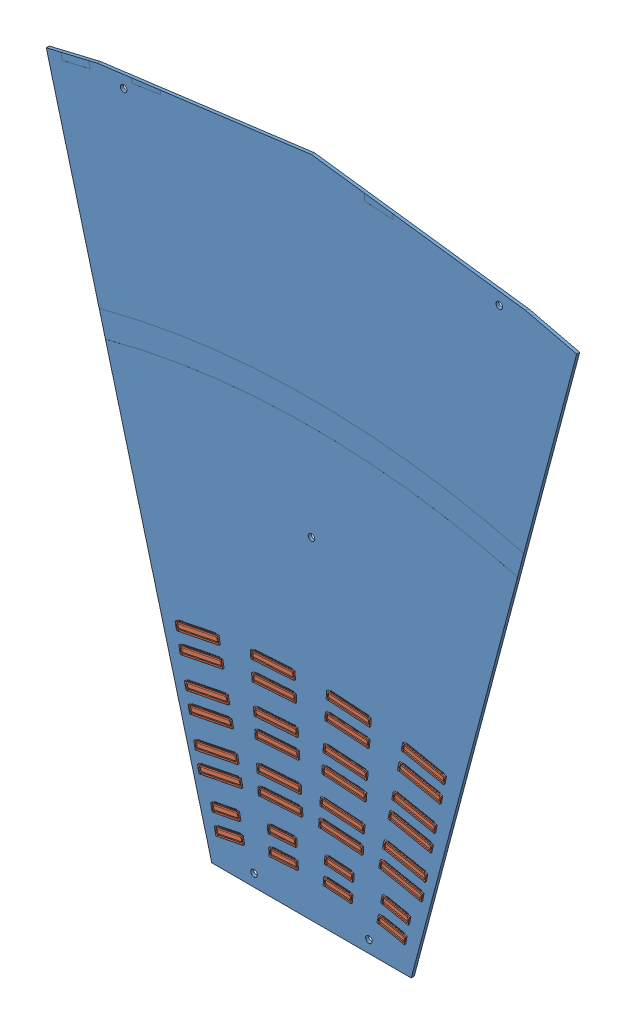
SolidWorks assembly FVTX rear_ckt_board_assy3, configuration outline drawing. Lengths in mm.
Overall size (276.95 346.3 2.31).
38 component instances, 3 part files, 20 mates.
Components (placement in the parent):
- FVTX rear_ckt_board_assy3-1: FVTX rear_ckt_board_assy3 [outline drawing] at origin size (276.95 346.3 1.59)
- hirose df18c series receptacle-4: hirose df18c series receptacle [DF18C-60DS-0.4V] at (-42.4321 213.3208 1.5875) x (0.19509 -0.980785 0) z (0 0 1)
- hirose df18c series receptacle-68: hirose df18c series receptacle [DF18C-60DS-0.4V] at (-44.383 223.1287 1.5875) x (0.19509 -0.980785 0) z (0 0 1)
- hirose df18c series receptacle-12: hirose df18c series receptacle [DF18C-100DS-0.4V] at (-47.3094 237.8404 1.5875) x (0.19509 -0.980785 0) z (0 0 1)
- hirose df18c series receptacle-41: hirose df18c series receptacle [DF18C-100DS-0.4V] at (-52.1867 262.3601 1.5875) x (0.19509 -0.980785 0) z (0 0 1)
- hirose df18c series receptacle-45: hirose df18c series receptacle [DF18C-100DS-0.4V] at (-57.0639 286.8797 1.5875) x (0.19509 -0.980785 0) z (0 0 1)
- hirose df18c series receptacle-65: hirose df18c series receptacle [DF18C-60DS-0.4V] at (-14.2252 217.0343 1.5875) x (0.065403 -0.997859 0) z (0 0 1)
- hirose df18c series receptacle-66: hirose df18c series receptacle [DF18C-60DS-0.4V] at (14.2252 217.0343 1.5875) x (-0.065403 -0.997859 0) z (0 0 1)
- hirose df18c series receptacle-67: hirose df18c series receptacle [DF18C-60DS-0.4V] at (42.4321 213.3208 1.5875) x (-0.19509 -0.980785 0) z (0 0 1)
- hirose df18c series receptacle-38: hirose df18c series receptacle [DF18C-100DS-0.4V] at (-15.8603 241.9808 1.5875) x (0.065403 -0.997859 0) z (0 0 1)
- hirose df18c series receptacle-39: hirose df18c series receptacle [DF18C-100DS-0.4V] at (15.8603 241.9808 1.5875) x (-0.065403 -0.997859 0) z (0 0 1)
- hirose df18c series receptacle-40: hirose df18c series receptacle [DF18C-100DS-0.4V] at (47.3094 237.8404 1.5875) x (-0.19509 -0.980785 0) z (0 0 1)
- hirose df18c series receptacle-42: hirose df18c series receptacle [DF18C-100DS-0.4V] at (-17.4953 266.9273 1.5875) x (0.065403 -0.997859 0) z (0 0 1)
- hirose df18c series receptacle-43: hirose df18c series receptacle [DF18C-100DS-0.4V] at (17.4953 266.9273 1.5875) x (-0.065403 -0.997859 0) z (0 0 1)
- hirose df18c series receptacle-44: hirose df18c series receptacle [DF18C-100DS-0.4V] at (52.1867 262.3601 1.5875) x (-0.19509 -0.980785 0) z (0 0 1)
- hirose df18c series receptacle-46: hirose df18c series receptacle [DF18C-100DS-0.4V] at (-19.1304 291.8737 1.5875) x (0.065403 -0.997859 0) z (0 0 1)
- hirose df18c series receptacle-47: hirose df18c series receptacle [DF18C-100DS-0.4V] at (19.1304 291.8737 1.5875) x (-0.065403 -0.997859 0) z (0 0 1)
- hirose df18c series receptacle-48: hirose df18c series receptacle [DF18C-100DS-0.4V] at (57.0639 286.8797 1.5875) x (-0.19509 -0.980785 0) z (0 0 1)
- VTX - pan cross head_ai-1: VTX - pan cross head_ai [CR-PHMS 0.112-40x0.25x0.25-N] at (-98.0409 523.0976 3.6195) x (0 0 -1) z (1 0 0) (suppressed, hidden)
- VTX - pan cross head_ai-2: VTX - pan cross head_ai [CR-PHMS 0.112-40x0.25x0.25-N] at (98.0409 523.0976 3.6195) x (0 0 -1) z (1 0 0) (suppressed, hidden)
- VTX - pan cross head_ai-3: VTX - pan cross head_ai [CR-PHMS 0.112-40x0.25x0.25-N] at (0 369.15 3.6195) x (0 0 -1) z (1 0 0) (suppressed, hidden)
- VTX - pan cross head_ai-4: VTX - pan cross head_ai [CR-PHMS 0.112-40x0.25x0.25-N] at (-30 202.35 3.6195) x (0 0 -1) z (1 0 0) (suppressed, hidden)
- VTX - pan cross head_ai-5: VTX - pan cross head_ai [CR-PHMS 0.112-40x0.25x0.25-N] at (30 202.35 3.6195) x (0 0 -1) z (1 0 0) (suppressed, hidden)
- hirose df18c series receptacle-69: hirose df18c series receptacle [DF18C-100DS-0.4V] at (-49.2603 247.6483 1.5875) x (0.19509 -0.980785 0) z (0 0 1)
- hirose df18c series receptacle-70: hirose df18c series receptacle [DF18C-100DS-0.4V] at (-54.1376 272.1679 1.5875) x (0.19509 -0.980785 0) z (0 0 1)
- hirose df18c series receptacle-71: hirose df18c series receptacle [DF18C-100DS-0.4V] at (-59.0148 296.6875 1.5875) x (0.19509 -0.980785 0) z (0 0 1)
- hirose df18c series receptacle-72: hirose df18c series receptacle [DF18C-60DS-0.4V] at (-14.8792 227.0129 1.5875) x (0.065403 -0.997859 0) z (0 0 1)
- hirose df18c series receptacle-73: hirose df18c series receptacle [DF18C-60DS-0.4V] at (14.8792 227.0129 1.5875) x (-0.065403 -0.997859 0) z (0 0 1)
- hirose df18c series receptacle-74: hirose df18c series receptacle [DF18C-60DS-0.4V] at (44.383 223.1287 1.5875) x (-0.19509 -0.980785 0) z (0 0 1)
- hirose df18c series receptacle-75: hirose df18c series receptacle [DF18C-100DS-0.4V] at (-16.5143 251.9594 1.5875) x (0.065403 -0.997859 0) z (0 0 1)
- hirose df18c series receptacle-76: hirose df18c series receptacle [DF18C-100DS-0.4V] at (16.5143 251.9594 1.5875) x (-0.065403 -0.997859 0) z (0 0 1)
- hirose df18c series receptacle-77: hirose df18c series receptacle [DF18C-100DS-0.4V] at (49.2603 247.6483 1.5875) x (-0.19509 -0.980785 0) z (0 0 1)
- hirose df18c series receptacle-78: hirose df18c series receptacle [DF18C-100DS-0.4V] at (-18.1494 276.9059 1.5875) x (0.065403 -0.997859 0) z (0 0 1)
- hirose df18c series receptacle-79: hirose df18c series receptacle [DF18C-100DS-0.4V] at (18.1494 276.9059 1.5875) x (-0.065403 -0.997859 0) z (0 0 1)
- hirose df18c series receptacle-80: hirose df18c series receptacle [DF18C-100DS-0.4V] at (54.1376 272.1679 1.5875) x (-0.19509 -0.980785 0) z (0 0 1)
- hirose df18c series receptacle-81: hirose df18c series receptacle [DF18C-100DS-0.4V] at (-19.7844 301.8523 1.5875) x (0.065403 -0.997859 0) z (0 0 1)
- hirose df18c series receptacle-82: hirose df18c series receptacle [DF18C-100DS-0.4V] at (19.7844 301.8523 1.5875) x (-0.065403 -0.997859 0) z (0 0 1)
- hirose df18c series receptacle-83: hirose df18c series receptacle [DF18C-100DS-0.4V] at (59.0148 296.6875 1.5875) x (-0.19509 -0.980785 0) z (0 0 1)
Mates (geometry in assembly coordinates):
- Coincident3: coincident aligned: plane of FVTX rear_ckt_board_assy3-1 through (0 0 0) normal (0 0 1); plane of assembly through (0 0 0) normal (0 0 1)
- Coincident31: coincident anti-aligned: plane of FVTX rear_ckt_board_assy3-1 through (-52.06 196 1.5875) normal (0 0 1); plane of hirose df18c series receptacle-4 through (-49.9821 213.8582 1.5875) normal (0 0 -1)
- Coincident33: coincident: plane of hirose df18c series receptacle-4; point of assembly
- Distance6: distance = 217.5 mm: plane of hirose df18c series receptacle-4; point of assembly
- Angle5: planar angle = 3.337942 rad anti-aligned: plane of hirose df18c series receptacle-4; plane of assembly through (0 0 0) normal (1 0 0)
- Coincident34: coincident aligned: line of FVTX rear_ckt_board_assy3-1 through (0 0 -0.0794) axis (0 0 1); line of assembly
- Parallel1: parallel aligned: plane of FVTX rear_ckt_board_assy3-1 through (0 0 0) normal (1 0 0); plane of assembly through (0 0 0) normal (1 0 0)
- Concentric11: concentric aligned: cylinder of FVTX rear_ckt_board_assy3-1 through (-85 474 0) axis (0 0 1) radius 1.7272; cylinder of VTX - pan cross head_ai-1 through (-85 474 29.0195) axis (0 0 1) radius 2.7813
- Coincident351: coincident anti-aligned: plane of FVTX rear_ckt_board_assy3-1 through (-51.7944 195 1.5875) normal (0 0 1); plane of VTX - pan cross head_ai-1 through (-85 475.4224 1.5875) normal (0 0 -1)
- Concentric21: concentric aligned: cylinder of FVTX rear_ckt_board_assy3-1 through (85 474 0) axis (0 0 1) radius 1.7272; cylinder of VTX - pan cross head_ai-2 through (85 474 29.0195) axis (0 0 1) radius 2.7813
- Coincident361: coincident anti-aligned: plane of FVTX rear_ckt_board_assy3-1 through (-51.7944 195 1.5875) normal (0 0 1); plane of VTX - pan cross head_ai-2 through (85 475.4224 1.5875) normal (0 0 -1)
- Concentric31: concentric aligned: cylinder of FVTX rear_ckt_board_assy3-1 through (0 343.25 0) axis (0 0 1) radius 1.7272; cylinder of VTX - pan cross head_ai-3 through (0 343.25 29.0195) axis (0 0 1) radius 2.7813
- Coincident371: coincident anti-aligned: plane of FVTX rear_ckt_board_assy3-1 through (-51.7944 195 1.5875) normal (0 0 1); plane of VTX - pan cross head_ai-3 through (0 344.6724 1.5875) normal (0 0 -1)
- Concentric41: concentric aligned: cylinder of FVTX rear_ckt_board_assy3-1 through (-30 201.35 0) axis (0 0 1) radius 1.7272; cylinder of VTX - pan cross head_ai-4 through (-30 201.35 29.0195) axis (0 0 1) radius 2.7813
- Coincident381: coincident anti-aligned: plane of FVTX rear_ckt_board_assy3-1 through (-51.7944 195 1.5875) normal (0 0 1); plane of VTX - pan cross head_ai-4 through (-30 202.7724 1.5875) normal (0 0 -1)
- Concentric51: concentric aligned: cylinder of FVTX rear_ckt_board_assy3-1 through (30 201.35 0) axis (0 0 1) radius 1.7272; cylinder of VTX - pan cross head_ai-5 through (30 201.35 29.0195) axis (0 0 1) radius 2.7813
- Coincident391: coincident anti-aligned: plane of FVTX rear_ckt_board_assy3-1 through (-51.7944 195 1.5875) normal (0 0 1); plane of VTX - pan cross head_ai-5 through (30 202.7724 1.5875) normal (0 0 -1)
- Coincident392: coincident aligned: plane of hirose df18c series receptacle-4 through (-42.4321 213.3208 1.5875) normal (0 0 1); plane of hirose df18c series receptacle-68 through (-44.383 223.1287 1.5875) normal (0 0 1)
- Coincident393: coincident aligned: plane of hirose df18c series receptacle-4; plane of hirose df18c series receptacle-68
- Distance7: distance = 10 mm aligned: unknown of hirose df18c series receptacle-4; unknown of hirose df18c series receptacle-68
